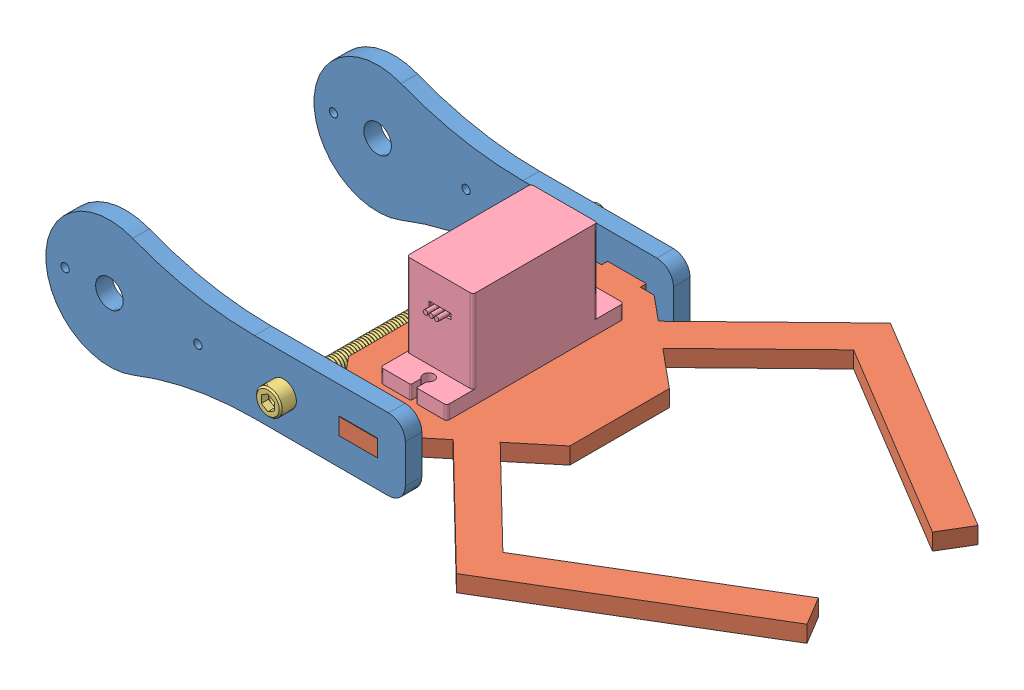
SolidWorks assembly link_3_littleRobot, configuration Predeterminado. Lengths in mm.
Overall size (127.85 30.45 78.46).
5 component instances, 4 part files, 12 mates.
Components (placement in the parent):
- F_pieza_arm_robot_v0-1: F_pieza_arm_robot_v0 [Predeterminado] at (113.5 126.5 26) x (0 -1 0) z (0 0 -1) size (23 65 3)
- F_pieza_arm_robot_v0-2: F_pieza_arm_robot_v0 [Predeterminado] at (113.5 126.5 -22.5) x (0 -1 0) z (0 0 -1) size (23 65 3)
- G_pieza_arm_robot_v0-1: G_pieza_arm_robot_v0 [Predeterminado] at (158.5 124.95 0.75) x (0 0 1) z (0 1 0) size (78.46 83.35 3)
- socket head cap screw_ai-13: socket head cap screw_ai [HX-SHCS 0.112-48x2.25x2.25-S] at (145 126.5 28.8448) x (0 0 -1) z (1 0 0) size (59.99 4.65 4.65)
- Towerpro Micro Servo 9g-1: Towerpro Micro Servo 9g [Varsayılan] at (159.5 145.45 1) x (1 0 0) z (0 0 -1) size (12 30 32)
Mates (geometry in assembly coordinates):
- Concéntrica16: concentric anti-aligned: cylinder of Servomoteur Futuba S3003-2/Axe-1 through (113.5 126.5 8.5) axis (0 0 1) radius 2.5; cylinder of F_pieza_arm_robot_v0-1 through (113.5 126.5 26) axis (0 0 -1) radius 2.5
- Coincidente21: coincident anti-aligned: plane of F_pieza_arm_robot_v0-1 through (155 124.95 26) normal (0 1 0); plane of G_pieza_arm_robot_v0-1 through (158.5 124.95 0.75) normal (0 -1 0)
- Coincidente23: coincident aligned: plane of F_pieza_arm_robot_v0-1 through (113.5 126.5 26) normal (0 0 1); plane of G_pieza_arm_robot_v0-1 through (158.5 127.95 26) normal (0 0 1)
- Coincidente24: coincident anti-aligned: plane of F_pieza_arm_robot_v0-1 through (162 124.95 26) normal (-1 0 0); plane of G_pieza_arm_robot_v0-1 through (162 127.95 0.75) normal (1 0 0)
- Coincidente25: coincident anti-aligned: plane of F_pieza_arm_robot_v0-2 through (155 124.95 -22.5) normal (0 1 0); plane of G_pieza_arm_robot_v0-1 through (158.5 124.95 0.75) normal (0 -1 0)
- Concéntrica33: concentric anti-aligned: cylinder of F_pieza_arm_robot_v0-1 through (145 126.5 26) axis (0 0 -1) radius 1.5; cylinder of socket head cap screw_ai-10 through (138.4716 144.3994 -69.9206) axis (0.763622 0 0.645663) radius 2.3241
- Coincidente39: coincident anti-aligned: plane of F_pieza_arm_robot_v0-1 through (113.5 126.5 26) normal (0 0 1); plane of socket head cap screw_ai-10 through (112.0542 146.7235 -92.2572) normal (-0.763622 0 -0.645663)
- Concéntrica36: concentric anti-aligned: cylinder of F_pieza_arm_robot_v0-1 through (145 126.5 26) axis (0 0 -1) radius 1.5; cylinder of socket head cap screw_ai-13 through (145 126.5 60.5948) axis (0 0 1) radius 2.3241
- Coincidente42: coincident anti-aligned: plane of F_pieza_arm_robot_v0-1 through (113.5 126.5 26) normal (0 0 1); plane of socket head cap screw_ai-13 through (145 128.8241 26) normal (0 0 -1)
- Coincidente55: coincident anti-aligned: plane of G_pieza_arm_robot_v0-1 through (158.5 127.95 0.75) normal (0 1 0); plane of Towerpro Micro Servo 9g-1 through (165 127.95 -14.5) normal (0 -1 0)
- Distancia8: distance = 15 mm aligned: plane of Towerpro Micro Servo 9g-1 through (165.5 144.45 11.75) normal (1 0 0); plane of G_pieza_arm_robot_v0-1 through (180.5 127.95 0.75) normal (1 0 0)
- Distancia9: distance = 6 mm anti-aligned: plane of Towerpro Micro Servo 9g-1 through (160.2 127.95 17) normal (0 0 1); plane of F_pieza_arm_robot_v0-1 through (113.5 126.5 23) normal (0 0 -1)
